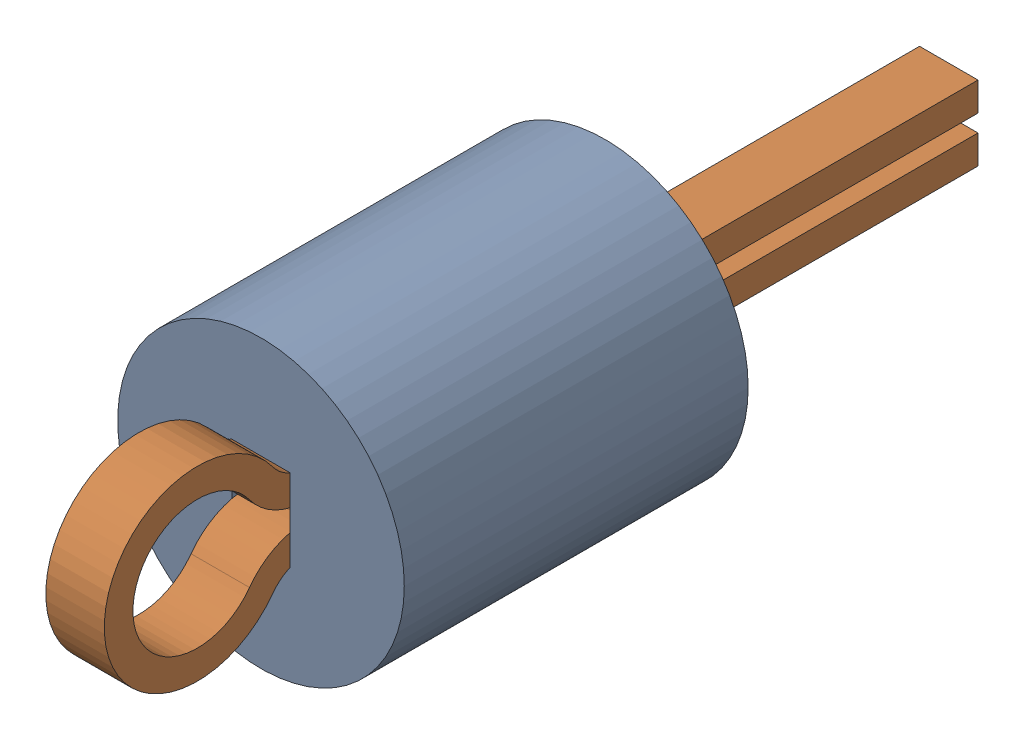
SolidWorks assembly TP6, configuration Default. Lengths in mm.
Overall size (2.5 2.5 7.62).
3 component instances, 2 part files, 0 mates.
Components (placement in the parent):
- Keystone_5002-1: Keystone_5002 [Default] at (18.2835 48.7709 0) size (2.5 2.5 7.62)
  - Keystone5002_white-1: Keystone5002_white [Default] at origin size (2.5 2.5 3)
  - Keystone500x_wire-1: Keystone500x_wire [Default] at origin size (0.51 1.62 7.62)
